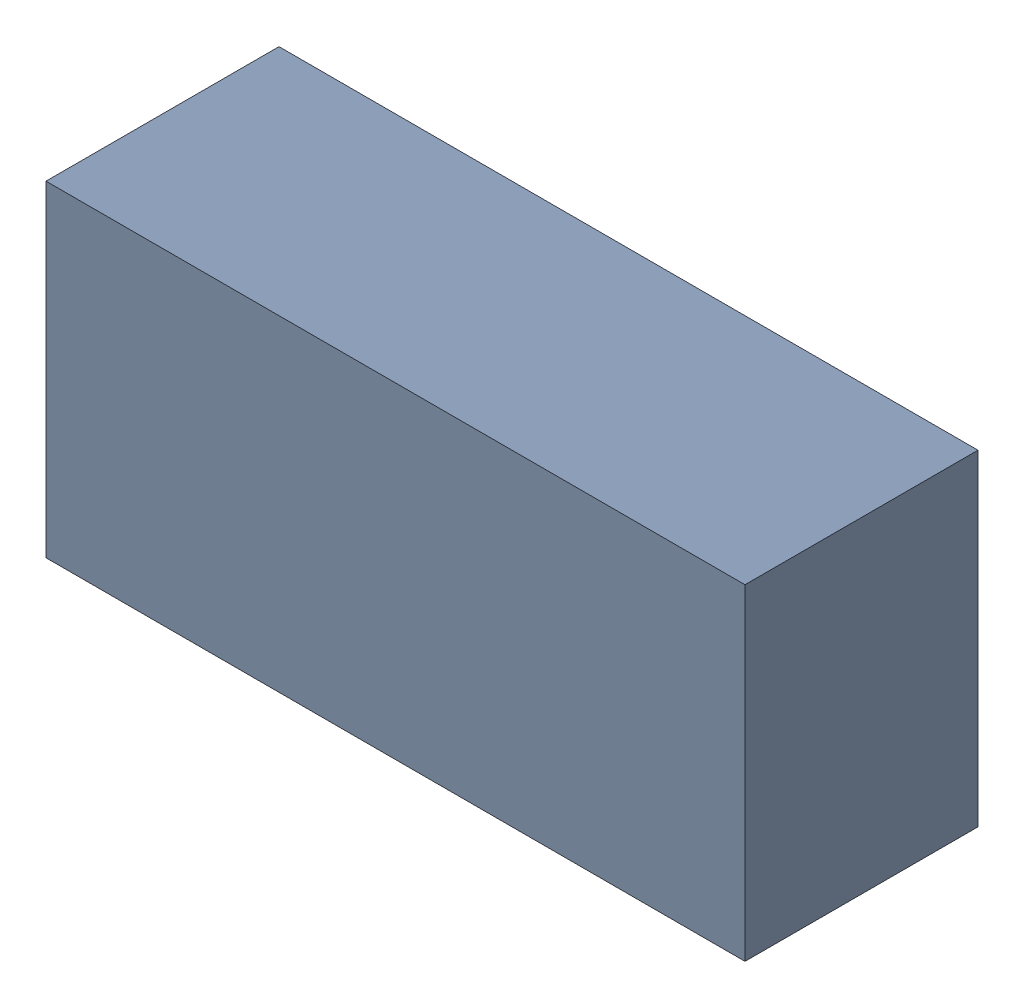
SolidWorks assembly Q1-1, configuration Default. Lengths in mm.
Overall size (3 1.4 1).
2 component instances, 1 part files, 0 mates.
Components (placement in the parent):
- 959206488-1-1: 959206488-1 [Default] at (75.057 92.3634 0.1) size (3 1.4 1)
  - Extruded-42-1: Extruded-42 [Default] at origin size (3 1.4 1)
